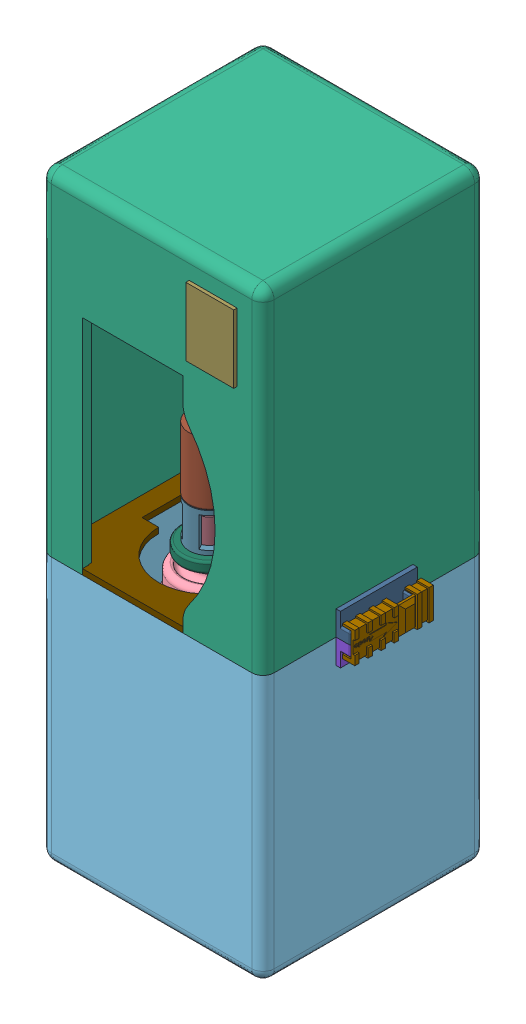
SolidWorks assembly Assem2, configuration Default. Lengths in mm.
Overall size (237.2 545 221.6).
78 component instances, 40 part files, 94 mates.
Components (placement in the parent):
- Assem_LinearActuator-1: Assem_LinearActuator [Default] at (35.3522 185.1381 133.8797) size (100 327.3 60)
  - Linear actuator_Top holder-1: Linear actuator_Top holder [Default] at (29.3485 49.5221 16.8235) x (1 0 0) z (0 -1 0) size (100 60 69.3)
  - Linear actuator_Bottom holder-1: Linear actuator_Bottom holder [Default] at (29.3485 -214.9779 17.8235) x (1 0 0) z (0 1 0) size (100 60 14)
  - Linear actuator_Circular guide-1: Linear actuator_Circular guide [Default] at (59.3485 -215.9779 16.8235) x (-0.72491 0 -0.688843) z (0.688843 0 -0.72491) size (8 260 8)
  - Linear actuator_Circular guide-2: Linear actuator_Circular guide [Default] at (-0.6515 44.0221 16.8235) x (0.999986 0 0.005294) z (0.005294 0 -0.999986) size (8 260 8)
- AssemV-Chiller-1: AssemV-Chiller [Default] at (28.581 15.2655 191.7135) size (100 255.81 129.09)
  - Top holder of can-1: Top holder of can [Default] at (36.1197 55.3594 37.5996) x (-1 0 0) z (0 0 1) size (65.8 35 65.8)
  - 250 ml CAN-1: 250 ml CAN [Default] at (36.1197 -108.6231 37.5996) x (0.908209 0 -0.418517) z (0.418517 0 0.908209) size (53.3 134.4 54.81)
  - 330 ml CAN-1: 330 ml CAN [Default] at (36.1197 -101.7316 37.5996) x (0 0 1) z (-1 0 0) size (58 146 58)
  - Screw M8x30-1: Screw M8x30 [Default] at (36.1197 60.7594 37.5996) x (-1 0 0) z (0 0 1) size (15.01 35.5 13)
  - Washer M8_ISO 7090-1: Washer M8_ISO 7090 [Default] at (36.1197 60.7594 37.5996) x (0.773857 0 0.63336) z (-0.63336 0 0.773857) size (16 1.6 16)
  - Screw nut M8-3: Screw nut M8 [Default] at (36.1197 66.9594 37.5996) x (0.505771 0 -0.862668) z (0 1 0) size (15.01 13 6.5)
  - Washer M8_ISO 7090-3: Washer M8_ISO 7090 [Default] at (36.1197 66.9594 37.5996) x (0.994262 0 -0.106973) z (-0.106973 0 -0.994262) size (16 1.6 16)
  - Bottom holder of can-1: Bottom holder of can [Default] at (36.1197 -110.6018 37.5996) x (0 0 -1) z (1 0 0) size (64 22 64)
  - Screw M8x30-2: Screw M8x30 [Default] at (36.1197 -105.0018 37.5999) x (0.840809 0 -0.541331) z (0.541331 0 0.840809) size (15.01 35.5 13)
  - Screw nut M8-4: Screw nut M8 [Default] at (36.1197 -118.7018 37.5999) x (0.505771 0 -0.862668) z (0 1 0) size (15.01 13 6.5)
  - Washer M8_ISO 7090-4: Washer M8_ISO 7090 [Default] at (36.1197 -105.0018 37.5996) x (0.987196 0 -0.159509) z (-0.159509 0 -0.987196) size (16 1.6 16)
  - Washer M8_ISO 7090-5: Washer M8_ISO 7090 [Default] at (36.1197 -110.6018 37.5999) x (0.987196 0 -0.159509) z (-0.159509 0 -0.987196) size (16 1.6 16)
  - Spring holder_Bottom-1: Spring holder_Bottom [Default] at (36.1197 -130.5018 25.0999) x (0 0 1) z (0 1 0) size (84.36 50 42)
  - Circular tube-1: Circular tube [Default] at (36.1197 -143.3406 -15.0604) size (100 231.6 45.4)
  - Bearing 608-1: Bearing 608 [Default] at (36.1197 -122.2018 37.5999) x (0 1 0) z (0.985159 0 -0.171644) size (7 22 22)
  - Screw nut M8-5: Screw nut M8 [Default] at (36.1197 -137.0018 37.5999) x (0.505771 0 -0.862668) z (0 1 0) size (15.01 13 6.5)
  - Cover of circular tube bottom-1: Cover of circular tube bottom [Default] at (36.1197 -161.3406 -15.5604) x (0 0 -1) z (1 0 0) size (19.4 3 28.4)
  - Holder of top bearing-1: Holder of top bearing [Default] at (36.1197 83.2594 25.0996) x (0 0 1) z (0 -1 0) size (87.86 50 10)
  - Bearing 608-2: Bearing 608 [Default] at (36.1197 76.9594 37.5996) x (0 1 0) z (0.985159 0 -0.171644) size (7 22 22)
  - 200 ml CAN-1: 200 ml CAN [Default] at (36.1197 -101.2229 37.5996) size (53.3 111.5 54.81)
  - Tension spring-2: Tension spring [Default] at (36.1197 -103.0957 -14.702) x (1 0 0) z (0 1 0) size (8.62 9.93 100.8)
  - 96817A522_THREAD-FORMING SCREW FOR THIN PLASTIC-1: 96817A522_THREAD-FORMING SCREW FOR THIN PLASTIC [96817A522] at (44.6197 79.8594 -18.2604) x (-0.165448 0 -0.986219) z (0 1 0) size (6.82 6.82 17.11)
  - 96817A522_THREAD-FORMING SCREW FOR THIN PLASTIC-2: 96817A522_THREAD-FORMING SCREW FOR THIN PLASTIC [96817A522] at (44.6197 79.8594 -3.2604) x (0.912516 0 0.409041) z (0 1 0) size (6.82 6.82 17.11)
  - 96817A522_THREAD-FORMING SCREW FOR THIN PLASTIC-3: 96817A522_THREAD-FORMING SCREW FOR THIN PLASTIC [96817A522] at (27.6197 79.8594 -3.2604) x (0.988371 0 0.152064) z (0 1 0) size (6.82 6.82 17.11)
  - 96817A522_THREAD-FORMING SCREW FOR THIN PLASTIC-4: 96817A522_THREAD-FORMING SCREW FOR THIN PLASTIC [96817A522] at (27.6197 79.8594 -18.2604) x (1 0 0) z (0 1 0) size (6.82 6.82 17.11)
  - Screw M5x50-1: Screw M5x50 [Default] at (36.1197 41.173 -15.0604) size (8.3 53.3 8.3)
  - HEX screw M5X40-2: HEX screw M5X40 [Default] at (78.1545 34.9594 -23.2604) x (1 0 0) z (0 -1 0) size (9.24 35.1 8)
  - HEX screw M5X40-3: HEX screw M5X40 [Default] at (78.1545 6.5594 -23.2604) x (1 0 0) z (0 -1 0) size (9.24 35.1 8)
  - Nut M5-1: Nut M5 [Default] at (36.1197 79.2594 -15.0604) size (9.24 4 8)
- Slider_Linear actuator-1: Slider_Linear actuator [Default] at (64.7007 36.0249 140.9532) size (100 45 23.5)
- PlexiglasBottom chamber-1: PlexiglasBottom chamber [Default] at (77.2007 -161.8398 193.7032) size (200 240 200)
- TOP_Plexiglas chamber-1: TOP_Plexiglas chamber [Default] at (77.2007 378.1602 193.7032) x (1 0 0) z (0 0 -1) size (200 300 200)
- Rubber leg-1: Rubber leg [Default] at (11.3404 -166.8398 260.5215) size (40 5 40)
- Rubber leg-2: Rubber leg [Default] at (11.3404 -166.8398 126.8848) size (40 5 40)
- Rubber leg-3: Rubber leg [Default] at (143.061 -166.8398 126.8848) x (-1 0 0) z (0 0 -1) size (40 5 40)
- Rubber leg-4: Rubber leg [Default] at (143.061 -166.8398 260.5215) x (-1 0 0) z (0 0 -1) size (40 5 40)
- Assem_Slider padlock-1: Assem_Slider padlock [Default] at (129.7751 28.2472 212.9479) x (0 0 -1) z (1 0 0) size (70.6 44 18.6)
  - Slider of padlock for BOTTOM chamber-1: Slider of padlock for BOTTOM chamber [Default] at (19.2447 38.913 48.4256) x (-1 0 0) z (0 1 0) size (69 13.5 22)
  - Padlock-1: Padlock [Default] at (12.4174 49.913 58.1756) size (70.6 27.5 12.9)
  - Slider of padlock for top chamber-1: Slider of padlock for top chamber [Default] at (19.2447 60.913 48.4256) x (1 0 0) z (0 -1 0) size (69 13.5 22)
- Assem_Slider padlock-2: Assem_Slider padlock [Default] at (96.4454 28.2472 141.1287) x (-1 0 0) z (0 0 -1) size (70.6 44 18.6)
  - Slider of padlock for BOTTOM chamber-1: Slider of padlock for BOTTOM chamber [Default] at (19.2447 38.913 48.4256) x (-1 0 0) z (0 1 0) size (69 13.5 22)
  - Padlock-1: Padlock [Default] at (12.4174 49.913 58.1756) size (70.6 27.5 12.9)
  - Slider of padlock for top chamber-1: Slider of padlock for top chamber [Default] at (19.2447 60.913 48.4256) x (1 0 0) z (0 -1 0) size (69 13.5 22)
- Assem_Slider padlock-3: Assem_Slider padlock [Default] at (24.6263 28.2472 174.4584) x (0 0 1) z (-1 0 0) size (70.6 44 18.6)
  - Slider of padlock for BOTTOM chamber-1: Slider of padlock for BOTTOM chamber [Default] at (19.2447 38.913 48.4256) x (-1 0 0) z (0 1 0) size (69 13.5 22)
  - Padlock-1: Padlock [Default] at (12.4174 49.913 58.1756) size (70.6 27.5 12.9)
  - Slider of padlock for top chamber-1: Slider of padlock for top chamber [Default] at (19.2447 60.913 48.4256) x (1 0 0) z (0 -1 0) size (69 13.5 22)
- DC Motor-1: DC Motor [Default] at (64.7007 190.5249 229.3132) x (-0.799724 0 -0.600367) z (-0.600367 0 0.799724) size (36.5 80.5 36.5)
- 2.4 touch display-1: 2.4 touch display [Default] at (132.4507 324.5602 289.7032) size (55.5 73.2 72)
- Elastic joint d8-8-1: Elastic joint d8-8 [Default] at (64.7007 111.0249 229.3132) x (-0.987046 0 0.16044) z (-0.16044 0 -0.987046) size (20 25 20)
- Holder of DC motor-1: Holder of DC motor [Default] at (64.7007 129.5249 229.3132) x (-0.999921 0 -0.01253) z (0.01253 0 -0.999921) size (36 35 36)
- Nut M5-1: Nut M5 [Default] at (106.7355 21.8249 140.9532) x (0.951358 0.308088 0) z (-0.308088 0.951358 0) size (9.24 4 8)
- Nut M5-2: Nut M5 [Default] at (100.9785 231.9102 115.7032) x (1 0 0) z (0 1 0) size (9.24 4 8)
- NEMA 17 motor-1: NEMA 17 motor [Default] at (-1.7993 269.3102 137.393) x (0 0 -1) z (1 0 0) size (42.3 42.3 72)
- Belt-1: Belt [Default] at (65.1207 68.1569 137.393) x (0 0 -1) z (1 0 0) size (23.01 299.8 15)
- Water pump-1: Water pump [Default] at (21.3232 -131.8398 100.7032) size (55.5 57.2 41.9)
- Cover of TOP_Plexiglas chamber-2: Cover of TOP_Plexiglas chamber [Default] at (76.2007 80.6602 192.7032) size (191 5 196.5)
- Screw pole-1: Screw pole [Default] at (64.7007 99.6602 112.7032) x (0.465684 0 0.884951) z (0 -1 0) size (8 8 153)
- Pulley-1: Pulley [Default] at (58.7871 269.3102 137.393) size (25.92 22.01 22.01)
- Pulley-2: Pulley [Default] at (58.7871 -7.4798 137.393) size (25.92 22.01 22.01)
- Pin Pulley-1: Pin Pulley [Default] at (86.1607 -7.4798 137.393) x (0 -0.173809 0.984779) z (0 -0.984779 -0.173809) size (8.01 50 8.01)
- Rubber seal-1: Rubber seal [Default] at (92.2332 -7.4798 137.393) x (0 0.791713 0.610893) z (0 -0.610893 0.791713) size (22.3 7 22.3)
- Rubber seal-2: Rubber seal [Default] at (30.1082 -7.4798 137.393) x (0 0.826577 0.562824) z (0 0.562824 -0.826577) size (22.3 7 22.3)
- Washer M8_ISO 7090-1: Washer M8_ISO 7090 [Default] at (64.7007 84.7602 112.7032) x (0.994262 0 -0.106973) z (-0.106973 0 -0.994262) size (16 1.6 16)
- Screw nut M8-1: Screw nut M8 [Default] at (64.7007 84.7602 112.7032) x (0.505771 0 -0.862668) z (0 1 0) size (15.01 13 6.5)
- Washer M8_ISO 7090-2: Washer M8_ISO 7090 [Default] at (64.7007 78.1602 112.7032) x (0.994262 0 -0.106973) z (-0.106973 0 -0.994262) size (16 1.6 16)
- Screw nut M8-2: Screw nut M8 [Default] at (64.7007 70.0602 112.7032) x (0.505771 0 -0.862668) z (0 1 0) size (15.01 13 6.5)
- Screw nut M8-3: Screw nut M8 [Default] at (64.7007 -44.9398 112.7032) x (0.505771 0 -0.862668) z (0 1 0) size (15.01 13 6.5)
- Washer M8_ISO 7090-3: Washer M8_ISO 7090 [Default] at (64.7007 -36.8398 112.7032) x (0.994262 0 -0.106973) z (-0.106973 0 -0.994262) size (16 1.6 16)
- Screw nut M8-4: Screw nut M8 [Default] at (64.7007 -21.2398 112.7032) x (0.505771 0 -0.862668) z (0 1 0) size (15.01 13 6.5)
- Washer M8_ISO 7090-4: Washer M8_ISO 7090 [Default] at (64.7007 -21.2398 112.7032) x (0.922566 0 0.385839) z (0.385839 0 -0.922566) size (16 1.6 16)
Mates (geometry in assembly coordinates):
- Concentric1: concentric aligned: cylinder of Assem_LinearActuator-1/Linear actuator_Circular guide-2 through (34.7007 -30.8398 150.7032) axis (0 1 0) radius 4; cylinder of Slider_Linear actuator-1 through (34.7007 13.5249 150.7032) axis (0 1 0) radius 4
- Parallel1: parallel aligned: plane of Assem_LinearActuator-1/Linear actuator_Top holder-1 through (64.7007 248.1602 150.7032) normal (0 1 0); plane of Slider_Linear actuator-1 through (114.7007 58.5249 160.4532) normal (0 1 0)
- Concentric2: concentric anti-aligned: cylinder of Assem_LinearActuator-1/Linear actuator_Circular guide-1 through (94.7007 229.1602 150.7032) axis (0 -1 0) radius 4; cylinder of Slider_Linear actuator-1 through (94.7007 13.5249 150.7032) axis (0 1 0) radius 4
- Coincident1: coincident anti-aligned: plane of AssemV-Chiller-1/Circular tube-1 through (64.7007 -128.0751 160.4532) normal (0 0 -1); plane of Slider_Linear actuator-1 through (64.7007 36.0249 160.4532) normal (0 0 1)
- Width1: width anti-aligned: plane of AssemV-Chiller-1/Circular tube-1 through (14.7007 58.5249 172.4532) normal (-1 0 0); plane of AssemV-Chiller-1/Circular tube-1 through (114.7007 58.5249 172.4532) normal (1 0 0); plane of Slider_Linear actuator-1 through (114.7007 58.5249 160.4532) normal (1 0 0); plane of Slider_Linear actuator-1 through (14.7007 58.5249 160.4532) normal (-1 0 0)
- Coincident2: coincident: plane of AssemV-Chiller-1/Circular tube-1 through (14.7007 58.5249 172.4532) normal (0 1 0); line of Slider_Linear actuator-1 through (114.7007 58.5249 140.9532) axis (-1 0 0)
- Coincident3: coincident aligned: plane of PlexiglasBottom chamber-1 through (177.2007 78.1602 93.7032) normal (1 0 0); plane of TOP_Plexiglas chamber-1 through (177.2007 78.1602 293.7032) normal (1 0 0)
- Coincident4: coincident aligned: plane of PlexiglasBottom chamber-1 through (177.2007 78.1602 93.7032) normal (0 0 -1); plane of TOP_Plexiglas chamber-1 through (177.2007 78.1602 93.7032) normal (0 0 -1)
- Coincident7: coincident anti-aligned: plane of Assem_LinearActuator-1/Linear actuator_Bottom holder-1 through (64.7007 -19.3398 150.7032) normal (0 -1 0); plane of ? through (64.7007 -19.3398 124.7832) normal (0 1 0)
- Width2: width anti-aligned: plane of ? through (89.7007 -19.3398 107.2832) normal (1 0 0); plane of ? through (39.7007 -19.3398 107.2832) normal (-1 0 0); plane of Assem_LinearActuator-1/Linear actuator_Bottom holder-1 through (22.2007 -7.3398 140.7032) normal (-1 0 0); plane of Assem_LinearActuator-1/Linear actuator_Bottom holder-1 through (107.2007 -7.3398 140.7032) normal (1 0 0)
- Coincident8: coincident aligned: plane of Assem_LinearActuator-1/Linear actuator_Bottom holder-1 through (22.2007 -7.3398 107.2832) normal (0 0 -1); plane of ? through (39.7007 -19.3398 107.2832) normal (0 0 -1)
- Coincident9: coincident anti-aligned: plane of PlexiglasBottom chamber-1 through (77.2007 -161.8398 193.7032) normal (0 -1 0); plane of Rubber leg-1 through (11.3404 -161.8398 260.5215) normal (0 1 0)
- Coincident11: coincident anti-aligned: plane of PlexiglasBottom chamber-1 through (164.7007 70.6606 95.1631) normal (1 0 0); plane of ? through (164.7007 70.8819 198.3861) normal (-1 0 0)
- Coincident12: coincident anti-aligned: plane of TOP_Plexiglas chamber-1 through (177.2007 78.1602 93.7032) normal (0 0 -1); plane of Assem_Slider padlock-2/Slider of padlock for top chamber-1 through (77.2007 89.1602 93.7032) normal (0 0 1)
- Coincident13: coincident anti-aligned: plane of TOP_Plexiglas chamber-1 through (-22.7993 78.1602 293.7032) normal (-1 0 0); plane of Assem_Slider padlock-3/Slider of padlock for top chamber-1 through (-22.7993 89.1602 193.7032) normal (1 0 0)
- Parallel2: parallel aligned: plane of Assem_Slider padlock-2/Slider of padlock for top chamber-1 through (42.7007 100.1602 93.7032) normal (0 1 0); plane of Assem_Slider padlock-3/Slider of padlock for top chamber-1 through (-22.7993 100.1602 228.2032) normal (0 1 0)
- Coincident15: coincident anti-aligned: plane of TOP_Plexiglas chamber-1 through (177.2007 78.1602 293.7032) normal (1 0 0); plane of Assem_Slider padlock-1/Slider of padlock for top chamber-1 through (177.2007 89.1602 193.7032) normal (-1 0 0)
- Parallel6: parallel aligned: plane of TOP_Plexiglas chamber-1 through (83.8927 373.3969 193.3755) normal (0 1 0); plane of ? through (83.8927 76.8451 193.3755) normal (0 1 0)
- Coincident21: coincident anti-aligned: plane of TOP_Plexiglas chamber-1 through (183.8927 73.3969 100.3755) normal (0 0 1); plane of ? through (173.8927 76.8451 100.3755) normal (0 0 -1)
- Coincident22: coincident anti-aligned: plane of PlexiglasBottom chamber-1 through (83.8927 72.8451 193.3755) normal (0 1 0); plane of ? through (83.8927 72.8451 193.3755) normal (0 -1 0)
- Coincident23: coincident anti-aligned: plane of TOP_Plexiglas chamber-1 through (176.8927 73.3969 293.3755) normal (-1 0 0); plane of ? through (176.8927 76.8451 283.3755) normal (1 0 0)
- Parallel7: parallel aligned: plane of Assem_Slider padlock-1/Slider of padlock for top chamber-1 through (177.2007 100.1602 228.2032) normal (0 0 1); plane of Assem_Slider padlock-3/Slider of padlock for top chamber-1 through (-22.7993 100.1602 228.2032) normal (0 0 1)
- Parallel8: parallel aligned: plane of Assem_Slider padlock-1/Slider of padlock for top chamber-1 through (177.2007 100.1602 228.2032) normal (0 0 1); plane of Assem_Slider padlock-3/Slider of padlock for top chamber-1 through (-22.7993 100.1602 228.2032) normal (0 0 1)
- Parallel9: parallel aligned: plane of Assem_Slider padlock-1/Slider of padlock for top chamber-1 through (177.2007 100.1602 228.2032) normal (0 0 1); plane of Assem_Slider padlock-3/Slider of padlock for top chamber-1 through (-22.7993 100.1602 228.2032) normal (0 0 1)
- Parallel10: parallel aligned: plane of Assem_Slider padlock-1/Slider of padlock for top chamber-1 through (177.2007 100.1602 159.2032) normal (0 1 0); plane of Assem_Slider padlock-3/Slider of padlock for top chamber-1 through (-22.7993 100.1602 228.2032) normal (0 1 0)
- Coincident28: coincident: plane of ? through (64.7007 259.2922 228.5634) normal (0 1 0); plane of Elastic joint d8-8-1 through (64.7007 259.2922 228.5634) normal (0 -1 0)
- Concentric7: concentric aligned: cylinder of AssemV-Chiller-1/Screw M8x30-1 through (64.7007 106.0249 229.3132) axis (0 -1 0) radius 4; cylinder of Elastic joint d8-8-1 through (64.7007 123.5249 229.3132) axis (0 -1 0) radius 4
- Coincident29: coincident anti-aligned: plane of AssemV-Chiller-1/Holder of top bearing-1 through (168.7526 98.5249 161.2923) normal (0 1 0); plane of Elastic joint d8-8-1 through (64.7007 98.5249 229.3132) normal (0 -1 0)
- Concentric8: concentric aligned: cylinder of DC Motor-1 through (64.7007 127.5249 229.3132) axis (0 -1 0) radius 3.9; cylinder of Elastic joint d8-8-1 through (64.7007 123.5249 229.3132) axis (0 -1 0) radius 4
- Concentric9: concentric anti-aligned: cylinder of DC Motor-1 through (64.7007 128.5249 229.3132) axis (0 1 0) radius 6.5; cylinder of Holder of DC motor-1 through (64.7007 133.5249 229.3132) axis (0 -1 0) radius 7
- Concentric10: concentric anti-aligned: cylinder of AssemV-Chiller-1/HEX screw M5X40-3 through (106.7355 21.8249 136.9532) axis (0 0 1) radius 2.5; cylinder of Nut M5-1 through (106.7355 21.8249 136.9532) axis (0 0 -1) radius 2.1
- Coincident32: coincident anti-aligned: plane of Slider_Linear actuator-1 through (64.7007 36.0249 140.9532) normal (0 0 -1); plane of Nut M5-1 through (106.7355 21.8249 140.9532) normal (0 0 1)
- Coincident33: coincident anti-aligned: plane of Assem_LinearActuator-1/Linear actuator_Top holder-1 through (95.2007 238.1602 111.7032) normal (0 0 1); plane of Nut M5-2 through (100.9785 231.9102 111.7032) normal (0 0 -1)
- Concentric11: concentric aligned: cylinder of Assem_LinearActuator-1/Linear actuator_Top holder-1 through (100.9785 231.9102 111.7032) axis (0 0 -1) radius 2.75; cylinder of Nut M5-2 through (100.9785 231.9102 111.7032) axis (0 0 -1) radius 2.1
- Parallel11: parallel aligned: plane of Assem_LinearActuator-1/Linear actuator_Top holder-1 through (64.7007 238.1602 150.7032) normal (0 -1 0); plane of Nut M5-2 through (103.2879 227.9102 111.7032) normal (0 -1 0)
- Coincident36: coincident anti-aligned: plane of AssemV-Chiller-1/Holder of top bearing-1 through (168.7526 98.5249 161.2923) normal (0 1 0); plane of Holder of DC motor-1 through (64.7007 98.5249 229.3132) normal (0 -1 0)
- Coincident37: coincident anti-aligned: plane of DC Motor-1 through (64.7007 133.5249 229.3132) normal (0 -1 0); plane of Holder of DC motor-1 through (64.7007 133.5249 229.3132) normal (0 1 0)
- Coincident40: coincident anti-aligned: plane of Assem_Slider padlock-1/Slider of padlock for top chamber-1 through (196.6807 82.0066 216.6432) normal (1 0 0); plane of ? through (196.6807 82.426 193.3444) normal (-1 0 0)
- Coincident41: coincident anti-aligned: plane of PlexiglasBottom chamber-1 through (177.2007 78.1602 100.7032) normal (0 0 1); plane of Water pump-1 through (21.3232 -131.8398 100.7032) normal (0 0 -1)
- Coincident43: coincident anti-aligned: plane of PlexiglasBottom chamber-1 through (77.2007 -154.8398 193.7032) normal (0 1 0); plane of Water pump-1 through (7.9232 -154.8398 106.9278) normal (0 -1 0)
- Coincident44: coincident anti-aligned: plane of Assem_LinearActuator-1/Linear actuator_Top holder-1 through (14.7007 221.1602 101.7032) normal (0 0 -1); plane of TOP_Plexiglas chamber-1 through (177.2007 78.1602 101.7032) normal (0 0 1)
- Coincident46: coincident anti-aligned: plane of PlexiglasBottom chamber-1 through (77.2007 78.1602 193.7032) normal (0 1 0); plane of TOP_Plexiglas chamber-1 through (77.2007 78.1602 193.7032) normal (0 -1 0)
- Width4: width anti-aligned: plane of Assem_Slider padlock-1/Slider of padlock for top chamber-1 through (177.2007 100.1602 228.2032) normal (0 0 1); plane of Assem_Slider padlock-1/Slider of padlock for top chamber-1 through (177.2007 100.1602 159.2032) normal (0 0 -1); plane of TOP_Plexiglas chamber-1 through (177.2007 78.1602 93.7032) normal (0 0 -1); plane of TOP_Plexiglas chamber-1 through (177.2007 78.1602 293.7032) normal (0 0 1)
- Width5: width anti-aligned: plane of Assem_Slider padlock-2/Slider of padlock for top chamber-1 through (111.7007 100.1602 93.7032) normal (1 0 0); plane of Assem_Slider padlock-2/Slider of padlock for top chamber-1 through (42.7007 100.1602 93.7032) normal (-1 0 0); plane of TOP_Plexiglas chamber-1 through (-22.7993 78.1602 293.7032) normal (-1 0 0); plane of TOP_Plexiglas chamber-1 through (177.2007 78.1602 293.7032) normal (1 0 0)
- Coincident51: coincident: line of TOP_Plexiglas chamber-1 through (-22.7993 78.1602 283.7032) axis (0 0 -1); plane of Assem_Slider padlock-3/Slider of padlock for BOTTOM chamber-1 through (-22.7993 78.1602 159.2032) normal (0 1 0)
- Width6: width anti-aligned: plane of Assem_Slider padlock-3/Slider of padlock for top chamber-1 through (-22.7993 100.1602 159.2032) normal (0 0 -1); plane of Assem_Slider padlock-3/Slider of padlock for top chamber-1 through (-22.7993 100.1602 228.2032) normal (0 0 1); plane of TOP_Plexiglas chamber-1 through (177.2007 78.1602 293.7032) normal (0 0 1); plane of TOP_Plexiglas chamber-1 through (177.2007 78.1602 93.7032) normal (0 0 -1)
- Distance2: distance = 7 mm: plane of 2.4 touch display-1 through (160.2007 361.1602 293.7032) normal (0 1 0); line of TOP_Plexiglas chamber-1 through (167.2007 368.1602 285.7032) axis (-1 0 0)
- Distance3: distance = 7 mm: plane of 2.4 touch display-1 through (160.2007 361.1602 293.7032) normal (1 0 0); line of TOP_Plexiglas chamber-1 through (167.2007 78.1602 293.7032) axis (0 1 0)
- Coincident52: coincident aligned: plane of TOP_Plexiglas chamber-1 through (177.2007 78.1602 293.7032) normal (0 0 1); plane of 2.4 touch display-1 through (132.4507 324.5602 293.7032) normal (0 0 1)
- Lock3: lock: unknown of PlexiglasBottom chamber-1; unknown of Rubber leg-1
- Distance4: distance = 130 mm aligned: plane of Assem_LinearActuator-1/Linear actuator_Top holder-1 through (64.7007 248.1602 150.7032) normal (0 1 0); plane of TOP_Plexiglas chamber-1 through (77.2007 378.1602 193.7032) normal (0 1 0)
- Coincident53: coincident: line of PlexiglasBottom chamber-1 through (177.2007 78.1602 283.7032) axis (0 0 -1); plane of Assem_Slider padlock-1/Slider of padlock for BOTTOM chamber-1 through (177.2007 78.1602 228.2032) normal (0 1 0)
- Coincident54: coincident anti-aligned: plane of PlexiglasBottom chamber-1 through (80.7007 74.6602 194.7032) normal (0 1 0); plane of ? through (170.7007 74.6602 284.7032) normal (0 -1 0)
- Coincident55: coincident anti-aligned: plane of TOP_Plexiglas chamber-1 through (176.2007 80.1602 194.7032) normal (-1 0 0); plane of ? through (176.2007 79.6602 104.7032) normal (1 0 0)
- Coincident56: coincident: line of TOP_Plexiglas chamber-1 through (108.7007 80.1602 290.2032) axis (0 -1 0); plane of ? through (170.7007 79.6602 290.2032) normal (0 0 1)
- Coincident57: coincident: line of TOP_Plexiglas chamber-1 through (-12.7993 78.1602 93.7032) axis (1 0 0); plane of Assem_Slider padlock-2/Slider of padlock for BOTTOM chamber-1 through (111.7007 78.1602 93.7032) normal (0 1 0)
- Coincident58: coincident anti-aligned: plane of TOP_Plexiglas chamber-1 through (171.7007 83.6602 193.7032) normal (-1 0 0); plane of Cover of TOP_Plexiglas chamber-2 through (171.7007 83.1602 102.7032) normal (1 0 0)
- Coincident59: coincident anti-aligned: plane of PlexiglasBottom chamber-1 through (77.2007 78.1602 193.7032) normal (0 1 0); plane of Cover of TOP_Plexiglas chamber-2 through (166.2007 78.1602 282.7032) normal (0 -1 0)
- Coincident61: coincident: line of TOP_Plexiglas chamber-1 through (105.2007 83.6602 288.2032) axis (0 -1 0); plane of Cover of TOP_Plexiglas chamber-2 through (166.2007 83.1602 288.2032) normal (0 0 1)
- Concentric13: concentric anti-aligned: cylinder of Assem_LinearActuator-1/Linear actuator_Bottom holder-1 through (64.7007 -22.8398 112.7032) axis (0 -1 0) radius 4; cylinder of Screw pole-1 through (64.7007 -53.3398 112.7032) axis (0 1 0) radius 4
- Coincident62: coincident anti-aligned: plane of Assem_LinearActuator-1/Linear actuator_Top holder-1 through (64.7007 248.1602 150.7032) normal (0 1 0); plane of NEMA 17 motor-1 through (46.2007 248.1602 116.243) normal (0 -1 0)
- Concentric14: concentric aligned: cylinder of NEMA 17 motor-1 through (70.2007 269.3102 137.393) axis (-1 0 0) radius 2.5; cylinder of Pulley-1 through (58.7871 269.3102 137.393) axis (-1 0 0) radius 3.995
- Coincident64: coincident anti-aligned: plane of NEMA 17 motor-1 through (48.2007 269.3102 137.393) normal (1 0 0); plane of Pulley-1 through (48.2007 273.3052 137.393) normal (-1 0 0)
- Distance5: distance = 29.5 mm anti-aligned: plane of Assem_LinearActuator-1/Linear actuator_Top holder-1 through (14.7007 221.1602 161.7032) normal (-1 0 0); plane of TOP_Plexiglas chamber-1 through (-14.7993 78.1602 293.7032) normal (1 0 0)
- Concentric15: concentric aligned: cylinder of Belt-1 through (72.6207 269.3102 137.393) axis (-1 0 0) radius 9.105; cylinder of Pulley-1 through (58.7871 269.3102 137.393) axis (-1 0 0) radius 9.11
- Coincident65: coincident anti-aligned: plane of Belt-1 through (72.6207 269.3102 137.393) normal (1 0 0); plane of Pulley-1 through (72.6207 278.4202 137.393) normal (-1 0 0)
- Coincident66: coincident anti-aligned: plane of Assem_LinearActuator-1/Linear actuator_Top holder-1 through (46.2007 234.6602 150.7032) normal (-1 0 0); plane of NEMA 17 motor-1 through (46.2007 269.3102 137.393) normal (1 0 0)
- Concentric16: concentric aligned: cylinder of Assem_LinearActuator-1/Linear actuator_Top holder-1 through (52.2007 284.8102 152.893) axis (-1 0 0) radius 1.85; cylinder of NEMA 17 motor-1 through (46.2007 284.8102 152.893) axis (-1 0 0) radius 1.5
- Concentric17: concentric aligned: cylinder of Belt-1 through (72.6207 -7.4798 137.393) axis (-1 0 0) radius 9.105; cylinder of Pulley-2 through (58.7871 -7.4798 137.393) axis (-1 0 0) radius 9.11
- Coincident67: coincident anti-aligned: plane of Belt-1 through (72.6207 269.3102 137.393) normal (1 0 0); plane of Pulley-2 through (72.6207 1.6302 137.393) normal (-1 0 0)
- Concentric18: concentric anti-aligned: cylinder of Pulley-2 through (58.7871 -7.4798 137.393) axis (-1 0 0) radius 3.995; cylinder of Pin Pulley-1 through (36.1607 -7.4798 137.393) axis (1 0 0) radius 4.005
- Parallel12: parallel aligned: plane of Assem_LinearActuator-1/Linear actuator_Top holder-1 through (14.7007 221.1602 161.7032) normal (0 0 1); plane of Belt-1 through (72.6207 269.3102 148.898) normal (0 0 1)
- Width7: width anti-aligned: plane of Pin Pulley-1 through (86.1607 -7.4798 137.393) normal (1 0 0); plane of Pin Pulley-1 through (36.1607 -7.4798 137.393) normal (-1 0 0); plane of Pulley-2 through (48.2007 -3.4848 137.393) normal (-1 0 0); plane of Pulley-2 through (74.1207 -3.4848 137.393) normal (1 0 0)
- Concentric19: concentric aligned: cylinder of Pin Pulley-1 through (36.1607 -7.4798 137.393) axis (1 0 0) radius 4.005; cylinder of Rubber seal-1 through (92.2332 -7.4798 137.393) axis (1 0 0) radius 3.925
- Distance6: distance = 0.02 mm anti-aligned: plane of Rubber seal-1 through (74.1407 -0.2356 142.9827) normal (-1 0 0); plane of Pulley-2 through (74.1207 -3.4848 137.393) normal (1 0 0)
- Concentric21: concentric anti-aligned: cylinder of Pin Pulley-1 through (36.1607 -7.4798 137.393) axis (1 0 0) radius 4.005; cylinder of Rubber seal-2 through (30.1082 -7.4798 137.393) axis (-1 0 0) radius 3.925
- Coincident69: coincident anti-aligned: plane of Pulley-2 through (48.2007 -3.4848 137.393) normal (-1 0 0); plane of Rubber seal-2 through (48.2007 0.0834 142.5428) normal (1 0 0)
- Width8: width anti-aligned: plane of Screw pole-1 through (64.7007 -53.3398 112.7032) normal (0 -1 0); plane of Screw pole-1 through (64.7007 99.6602 112.7032) normal (0 1 0); plane of Cover of TOP_Plexiglas chamber-2 through (166.2007 83.1602 282.7032) normal (0 1 0); plane of Assem_LinearActuator-1/Linear actuator_Bottom holder-1 through (64.7007 -36.8398 151.7032) normal (0 -1 0)
- Coincident70: coincident anti-aligned: plane of Cover of TOP_Plexiglas chamber-2 through (166.2007 83.1602 282.7032) normal (0 1 0); plane of Washer M8_ISO 7090-1 through (64.7007 83.1602 112.7032) normal (0 -1 0)
- Concentric22: concentric aligned: cylinder of Screw pole-1 through (64.7007 -53.3398 112.7032) axis (0 1 0) radius 4; cylinder of Washer M8_ISO 7090-1 through (64.7007 83.1602 112.7032) axis (0 1 0) radius 4.2
- Coincident71: coincident anti-aligned: plane of Washer M8_ISO 7090-1 through (64.7007 84.7602 112.7032) normal (0 1 0); plane of Screw nut M8-1 through (64.7007 84.7602 112.7032) normal (0 -1 0)
- Concentric23: concentric aligned: cylinder of Screw pole-1 through (64.7007 -53.3398 112.7032) axis (0 1 0) radius 4; cylinder of Screw nut M8-1 through (64.7007 91.2602 112.7032) axis (0 1 0) radius 3.4
- Concentric241: concentric aligned: cylinder of Screw pole-1 through (64.7007 -53.3398 112.7032) axis (0 1 0) radius 4; cylinder of Washer M8_ISO 7090-2 through (64.7007 76.5602 112.7032) axis (0 1 0) radius 8
- Coincident72: coincident: line of Cover of TOP_Plexiglas chamber-2 through (118.2007 78.1602 121.7032) axis (0 0 1); plane of Washer M8_ISO 7090-2 through (64.7007 78.1602 112.7032) normal (0 1 0)
- Concentric25: concentric aligned: cylinder of Screw pole-1 through (64.7007 -53.3398 112.7032) axis (0 1 0) radius 4; cylinder of Screw nut M8-2 through (64.7007 76.5602 112.7032) axis (0 1 0) radius 3.4
- Coincident73: coincident anti-aligned: plane of Washer M8_ISO 7090-2 through (64.7007 76.5602 112.7032) normal (0 -1 0); plane of Screw nut M8-2 through (64.7007 76.5602 112.7032) normal (0 1 0)
- Concentric26: concentric aligned: cylinder of Screw pole-1 through (64.7007 -53.3398 112.7032) axis (0 1 0) radius 4; cylinder of Screw nut M8-3 through (64.7007 -38.4398 112.7032) axis (0 1 0) radius 3.4
- Coincident74: coincident anti-aligned: plane of Assem_LinearActuator-1/Linear actuator_Bottom holder-1 through (64.7007 -36.8398 151.7032) normal (0 -1 0); plane of Washer M8_ISO 7090-3 through (64.7007 -36.8398 112.7032) normal (0 1 0)
- Concentric27: concentric aligned: cylinder of Screw pole-1 through (64.7007 -53.3398 112.7032) axis (0 1 0) radius 4; cylinder of Washer M8_ISO 7090-3 through (64.7007 -38.4398 112.7032) axis (0 1 0) radius 4.2
- Coincident75: coincident anti-aligned: plane of Screw nut M8-3 through (64.7007 -38.4398 112.7032) normal (0 1 0); plane of Washer M8_ISO 7090-3 through (64.7007 -38.4398 112.7032) normal (0 -1 0)
- Concentric28: concentric aligned: cylinder of Screw pole-1 through (64.7007 -53.3398 112.7032) axis (0 1 0) radius 4; cylinder of Screw nut M8-4 through (64.7007 -0.4596 112.7032) axis (0 1 0) radius 3.4
- Concentric291: concentric aligned: cylinder of Screw pole-1 through (64.7007 -53.3398 112.7032) axis (0 1 0) radius 4; cylinder of Washer M8_ISO 7090-4 through (64.7007 -22.8398 112.7032) axis (0 1 0) radius 8
- Coincident77: coincident anti-aligned: plane of Assem_LinearActuator-1/Linear actuator_Bottom holder-1 through (64.7007 -22.8398 151.7032) normal (0 1 0); plane of Washer M8_ISO 7090-4 through (64.7007 -22.8398 112.7032) normal (0 -1 0)
- Coincident78: coincident anti-aligned: plane of Screw nut M8-4 through (64.7007 -21.2398 112.7032) normal (0 -1 0); plane of Washer M8_ISO 7090-4 through (64.7007 -21.2398 112.7032) normal (0 1 0)
